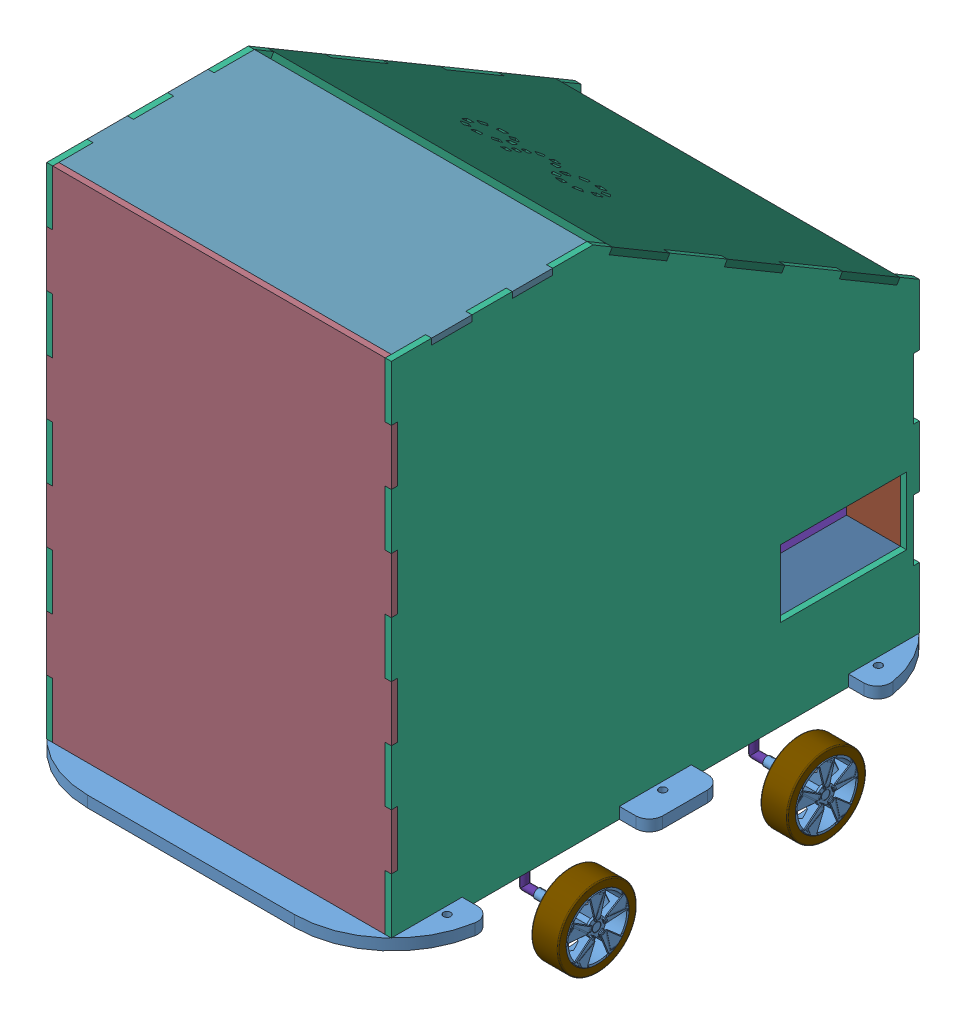
SolidWorks assembly Assem1, configuration Varsayılan. Lengths in mm.
Overall size (204.6 256.45 260).
53 component instances, 19 part files, 30 mates.
Components (placement in the parent):
- mainboard_last-1: mainboard_last [Varsayılan] at (-3.7025 2.4058 260) size (180 5 260)
- Assem-2: Assem [Varsayılan] at (36.9297 -4.2274 65.841) size (80 56 25)
  - holder_A_1-1: holder_A_1 [Varsayılan] at (-40.6321 11.6331 76.659) size (80 3 25)
  - holder_B_2-1: holder_B_2 [Varsayılan] at (-40.6321 20.6331 64.159) x (1 0 0) z (0 -1 0) size (80 3 56)
  - holder_C_1-1: holder_C_1 [Varsayılan] at (-40.6321 20.6331 70.159) x (1 0 0) z (0 -1 0) size (80 3 56)
  - holder_D_1-1: holder_D_1 [Varsayılan] at (-40.6321 52.6331 68.659) size (80 3 9)
- Side_2-10: Side_2 [Varsayılan] at (72.9975 117.2058 260) x (-1 0 0) z (0 0 -1) size (2.7 227.3 235.04)
- Assem for solar panel holder-4: Assem for solar panel holder [Varsayılan] at (45.3941 8.6486 146.17) size (35.5 68 62)
  - part_A1-1: part_A1 [Varsayılan] at (-0.5965 -1.2429 30) size (20 3 30)
  - part_B1-3: part_B1 [Varsayılan] at (-2.0965 32.7571 30) size (3 68 62)
  - Part_E1-1: Part_E1 [Varsayılan] at (11.4035 63.7571 30) x (0 0 -1) z (1 0 0) size (62 3 27)
  - Part_F1-1: Part_F1 [Varsayılan] at (11.4035 30.7571 30) x (0 0 -1) z (1 0 0) size (62 3 27)
  - Part_C1-1: Part_C1 [Varsayılan] at (12.9035 48.7571 2) x (0 0 -1) z (-1 0 0) size (3 36 24)
  - Part_D1-1: Part_D1 [Varsayılan] at (12.9035 48.7571 61) x (0 0 -1) z (1 0 0) size (3 36 24)
- Side_2-11: Side_2 [Varsayılan] at (-77.7025 117.2058 260.0067) x (-1 0 0) z (0 0 -1) size (2.7 227.3 235.04)
- Assem for solar panel holder-5: Assem for solar panel holder [Varsayılan] at (-52.799 8.6486 206.17) x (-1 0 0) z (0 0 -1) size (35.5 68 62)
  - part_A1-1: part_A1 [Varsayılan] at (-0.5965 -1.2429 30) size (20 3 30)
  - part_B1-3: part_B1 [Varsayılan] at (-2.0965 32.7571 30) size (3 68 62)
  - Part_E1-1: Part_E1 [Varsayılan] at (11.4035 63.7571 30) x (0 0 -1) z (1 0 0) size (62 3 27)
  - Part_F1-1: Part_F1 [Varsayılan] at (11.4035 30.7571 30) x (0 0 -1) z (1 0 0) size (62 3 27)
  - Part_C1-1: Part_C1 [Varsayılan] at (12.9035 48.7571 2) x (0 0 -1) z (-1 0 0) size (3 36 24)
  - Part_D1-1: Part_D1 [Varsayılan] at (12.9035 48.7571 61) x (0 0 -1) z (1 0 0) size (3 36 24)
- Back-1: Back [Varsayılan] at (-3.7025 116.0558 374.8267) size (153.4 227.3 2.7)
- Top_first-3: Top_first [Varsayılan] at (-3.7025 227.0058 332.6417) size (153.4 2.7 87.07)
- Top_second-2: Top_second [Varsayılan] at (-3.7025 184.4308 216.4945) x (-1 0 0) z (0 -0.508987 -0.860774) size (153.4 2.7 148.77)
- this little thing-1: this little thing [Varsayılan] at (63.361 -8.102 314.3) x (1 0 0) z (0 0 -1) size (13.3 13.3 3.3)
  - Part1-1: Part1 [Varsayılan] at (2.5366 1.1422 3.3) size (3.3 3.3 3.3)
  - Part2-1: Part2 [Varsayılan] at (2.5366 1.1422 3.3) size (11.65 3.3 3.3)
  - Part2-2: Part2 [Varsayılan] at (2.5366 1.1422 3.3) x (0 -1 0) z (0 0 -1) size (11.65 3.3 3.3)
- this little thing-2: this little thing [Varsayılan] at (67.0398 -11.7808 205.7) x (0 1 0) z (0 0 1) size (13.3 13.3 3.3)
  - Part1-1: Part1 [Varsayılan] at (2.5366 1.1422 3.3) size (3.3 3.3 3.3)
  - Part2-1: Part2 [Varsayılan] at (2.5366 1.1422 3.3) size (11.65 3.3 3.3)
  - Part2-2: Part2 [Varsayılan] at (2.5366 1.1422 3.3) x (0 -1 0) z (0 0 -1) size (11.65 3.3 3.3)
- this little thing-3: this little thing [Varsayılan] at (-70.7659 -8.102 307.7) x (-1 0 0) z (0 0 1) size (13.3 13.3 3.3)
  - Part1-1: Part1 [Varsayılan] at (2.5366 1.1422 3.3) size (3.3 3.3 3.3)
  - Part2-1: Part2 [Varsayılan] at (2.5366 1.1422 3.3) size (11.65 3.3 3.3)
  - Part2-2: Part2 [Varsayılan] at (2.5366 1.1422 3.3) x (0 -1 0) z (0 0 -1) size (11.65 3.3 3.3)
- this little thing-4: this little thing [Varsayılan] at (-70.7659 -8.102 205.7) x (-1 0 0) z (0 0 1) size (13.3 13.3 3.3)
  - Part1-1: Part1 [Varsayılan] at (2.5366 1.1422 3.3) size (3.3 3.3 3.3)
  - Part2-1: Part2 [Varsayılan] at (2.5366 1.1422 3.3) size (11.65 3.3 3.3)
  - Part2-2: Part2 [Varsayılan] at (2.5366 1.1422 3.3) x (0 -1 0) z (0 0 -1) size (11.65 3.3 3.3)
- roue-1: roue [Default] at (-85.6776 -46.1925 188.008) x (0 0 -1) z (1 0 0) size (35 35 26.8)
  - tire-1: tire [Default] at (-20.992 36.9482 -20.0249) size (35 35 12)
  - disque roue-1: disque roue [Default] at (-20.992 36.9482 -20.0249) size (28 28 26.8)
- roue-2: roue [Default] at (-85.6776 -46.1925 290.008) x (0 0 -1) z (1 0 0) size (35 35 26.8)
  - tire-1: tire [Default] at (-20.992 36.9482 -20.0249) size (35 35 12)
  - disque roue-1: disque roue [Default] at (-20.992 36.9482 -20.0249) size (28 28 26.8)
- roue-3: roue [Default] at (78.2727 -46.1925 229.992) x (0 0 1) z (-1 0 0) size (35 35 26.8)
  - tire-1: tire [Default] at (-20.992 36.9482 -20.0249) size (35 35 12)
  - disque roue-1: disque roue [Default] at (-20.992 36.9482 -20.0249) size (28 28 26.8)
- roue-4: roue [Default] at (78.2727 -46.1925 331.992) x (0 0 1) z (-1 0 0) size (35 35 26.8)
  - tire-1: tire [Default] at (-20.992 36.9482 -20.0249) size (35 35 12)
  - disque roue-1: disque roue [Default] at (-20.992 36.9482 -20.0249) size (28 28 26.8)
Mates (geometry in assembly coordinates):
- Coincident4: coincident aligned: circle of mainboard_last-1; circle of Assem-2/holder_A_1-1
- Coincident20: coincident aligned: plane of mainboard_last-1 through (-87.7025 2.4058 270) normal (0 -1 0); plane of Side_2-10 through (70.2975 2.4058 260) normal (0 -1 0)
- Coincident21: coincident anti-aligned: plane of mainboard_last-1 through (72.9975 7.4058 254.6667) normal (-1 0 0); plane of Side_2-10 through (72.9975 117.2058 260) normal (1 0 0)
- Coincident22: coincident anti-aligned: plane of mainboard_last-1 through (70.2975 7.4058 254.6667) normal (0 0 1); plane of Side_2-10 through (70.2975 117.2058 254.6667) normal (0 0 -1)
- Coincident25: coincident aligned: circle of mainboard_last-1; circle of Assem for solar panel holder-4/part_A1-1
- Coincident26: coincident anti-aligned: plane of mainboard_last-1 through (-77.7025 7.4058 174) normal (-1 0 0); plane of Side_2-11 through (-77.7025 117.2058 260.0067) normal (1 0 0)
- Coincident27: coincident anti-aligned: plane of mainboard_last-1 through (-77.7025 7.4058 367.02) normal (0 0 -1); plane of Side_2-11 through (-80.4025 117.2058 367.02) normal (0 0 1)
- Coincident29: coincident: plane of mainboard_last-1 through (-87.7025 2.4058 270) normal (0 -1 0); line of Side_2-11 through (-77.7025 2.4058 276.0067) axis (0 0 1)
- Coincident30: coincident aligned: circle of mainboard_last-1; circle of Assem for solar panel holder-5/part_A1-1
- Coincident31: coincident aligned: plane of Side_2-11 through (-80.4025 117.2058 377.5267) normal (0 0 1); plane of Back-1 through (-3.7025 116.0558 377.5267) normal (0 0 1)
- Coincident32: coincident aligned: plane of Side_2-11 through (-80.4025 229.7058 260.0067) normal (0 1 0); plane of Back-1 through (70.2975 229.7058 377.5267) normal (0 1 0)
- Coincident33: coincident aligned: plane of Side_2-10 through (72.9975 117.2058 260) normal (1 0 0); plane of Back-1 through (72.9975 180.3058 377.5267) normal (1 0 0)
- Coincident50: coincident aligned: plane of Side_2-11 through (-80.4025 117.2058 260.0067) normal (-1 0 0); plane of Top_first-3 through (-80.4025 229.7058 359.5727) normal (-1 0 0)
- Coincident51: coincident aligned: plane of Side_2-11 through (-80.4025 229.7058 260.0067) normal (0 1 0); plane of Top_first-3 through (-3.7025 229.7058 332.6417) normal (0 1 0)
- Coincident52: coincident anti-aligned: plane of Back-1 through (-3.7025 116.0558 374.8267) normal (0 0 -1); plane of Top_first-3 through (-77.7025 229.7058 374.8267) normal (0 0 1)
- Coincident53: coincident anti-aligned: plane of Side_2-11 through (-80.4025 153.4189 321.2486) normal (0 -0.508987 -0.860774); plane of Top_second-2 through (-80.4025 224.6159 279.1489) normal (0 0.508987 0.860774)
- Coincident54: coincident aligned: plane of Side_2-11 through (-80.4025 117.2058 260.0067) normal (-1 0 0); plane of Top_second-2 through (-80.4025 148.8939 151.0915) normal (-1 0 0)
- Coincident55: coincident: line of Side_2-11 through (-77.7025 179.1837 202.3162) axis (0 -0.508987 -0.860774); plane of Top_second-2 through (-3.7025 186.7549 215.1202) normal (0 0.860774 -0.508987)
- Coincident56: coincident aligned: circle of mainboard_last-1; circle of this little thing-1/Part2-2
- Coincident57: coincident aligned: circle of mainboard_last-1; circle of this little thing-2/Part2-1
- Coincident58: coincident aligned: circle of mainboard_last-1; circle of this little thing-3/Part2-2
- Coincident60: coincident aligned: circle of mainboard_last-1; circle of this little thing-4/Part2-2
- Concentric4: concentric anti-aligned: circle of this little thing-4/Part2-1; circle of roue-1/disque roue-1
- Coincident61: coincident anti-aligned: plane of mainboard_last-1 through (-93.7025 7.4058 270) normal (-1 0 0); plane of roue-1/tire-1 through (-93.7025 -9.2442 209) normal (1 0 0)
- Concentric5: concentric anti-aligned: circle of this little thing-3/Part2-1; circle of roue-2/disque roue-1
- Coincident65: coincident anti-aligned: plane of mainboard_last-1 through (-93.7025 7.4058 270) normal (-1 0 0); plane of roue-2/tire-1 through (-93.7025 -9.2442 311) normal (1 0 0)
- Concentric6: concentric anti-aligned: circle of this little thing-2/Part2-2; circle of roue-3/disque roue-1
- Coincident66: coincident anti-aligned: plane of mainboard_last-1 through (86.2975 7.4058 270) normal (1 0 0); plane of roue-3/tire-1 through (86.2975 -9.2442 209) normal (-1 0 0)
- Concentric7: concentric anti-aligned: circle of this little thing-1/Part2-1; circle of roue-4/disque roue-1
- Coincident69: coincident anti-aligned: plane of mainboard_last-1 through (86.2975 7.4058 270) normal (1 0 0); plane of roue-4/tire-1 through (86.2975 -9.2442 311) normal (-1 0 0)
